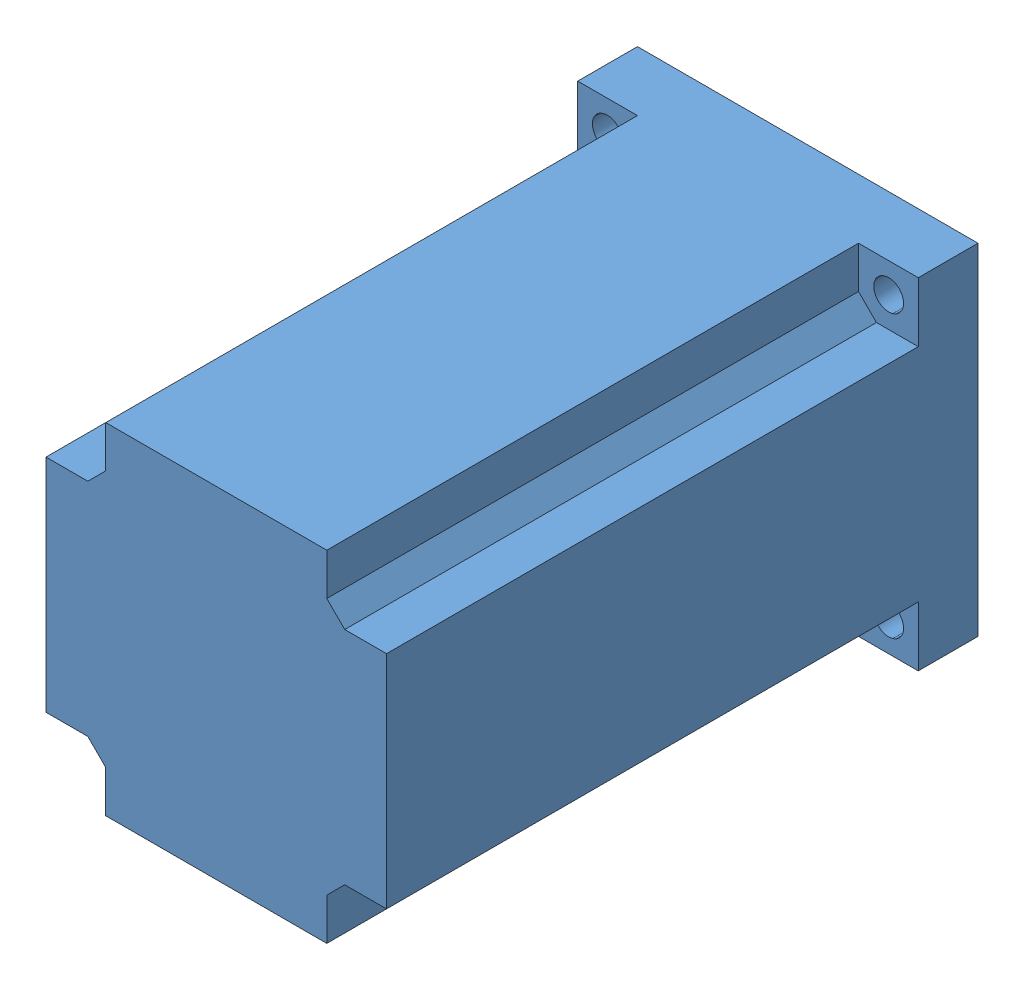
SolidWorks assembly 57 stepper motor, configuration Default. Lengths in mm.
Overall size (57 57 120).
2 component instances, 2 part files, 2 mates.
Components (placement in the parent):
- motor body-1: motor body [Default] at (21.3859 57.4242 33.703) size (57 57 100.6)
- motor axis-1: motor axis [Default] at (21.3859 57.4242 33.703) x (0.017268 -0.999851 0) z (0 0 -1) size (8 8 21)
Mates (geometry in assembly coordinates):
- Coincident5: coincident aligned: line of 57 stepper motor-1 through (21.3859 57.4242 32.103) axis (0 0 1); line of motor axis-1 through (21.3859 57.4242 12.703) axis (0 0 1)
- Coincident6: coincident anti-aligned: plane of motor axis-1 through (21.3859 57.4242 33.703) normal (0 0 1); plane of 57 stepper motor-1 through (21.3859 57.4242 33.703) normal (0 0 -1)
